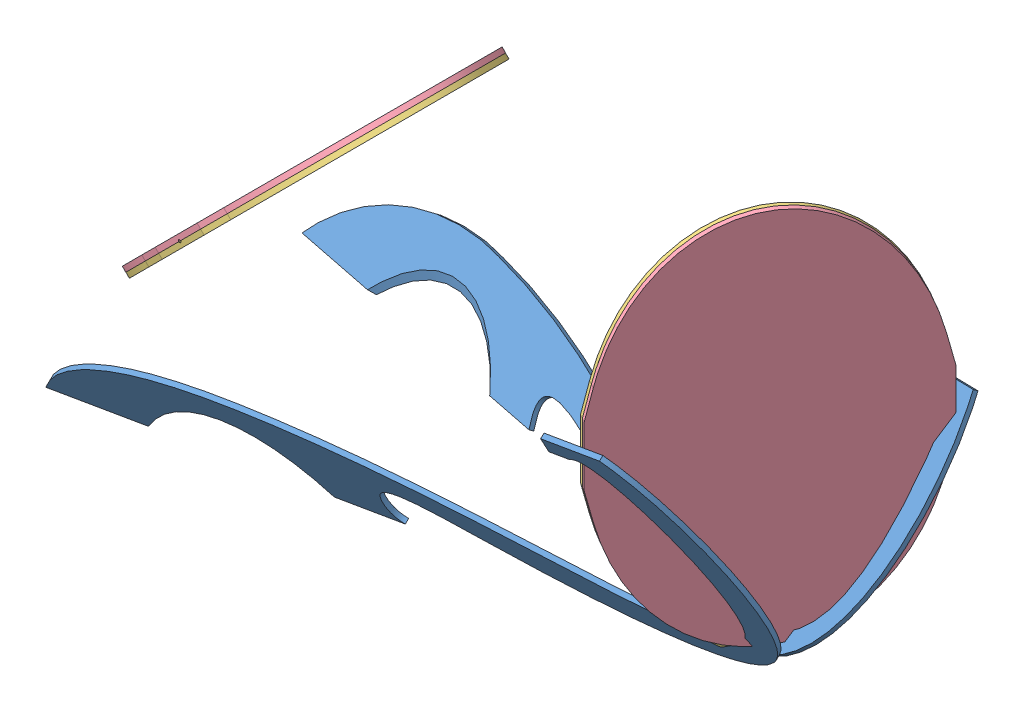
SolidWorks assembly Assem1, configuration Default. Lengths in mm.
Overall size (1381.46 832.52 597.36).
9 component instances, 4 part files, 6 mates.
Components (placement in the parent):
- Angled Side-1: Angled Side [Default] at (-297.1318 -28.8206 176.3727) size (1381.46 807.52 597.36)
- Mirror Assembly-1: Mirror Assembly [Default] at (-287.0354 425.802 60.3644) x (0 0 -1) z (-0.707107 -0.707107 0) size (550 20 760)
  - Mirror-1: Mirror [Default] at (-116.0082 27.9493 42.2276) size (520 4 730)
  - Mirror Front-1: Mirror Front [Default] at (-116.0082 27.9493 42.2276) size (550 10 756.61)
  - Mirror Back-1: Mirror Back [Default] at (-116.0082 27.9493 42.2276) x (-1 0 0) z (0 0 1) size (550 10 760)
- Mirror Assembly-2: Mirror Assembly [Default] at (583.6985 418.407 290.8134) x (-0.5 0 0.866025) z (0 -1 0) size (550 20 760)
  - Mirror-1: Mirror [Default] at (-116.0082 27.9493 42.2276) size (520 4 730)
  - Mirror Front-1: Mirror Front [Default] at (-116.0082 27.9493 42.2276) size (550 10 756.61)
  - Mirror Back-1: Mirror Back [Default] at (-116.0082 27.9493 42.2276) x (-1 0 0) z (0 0 1) size (550 10 760)
Mates (geometry in assembly coordinates):
- Coincident1: coincident: plane of Angled Side-1 through (-499.6318 173.6794 176.3727) normal (0.707107 -0.707107 0); plane of Mirror Assembly-1/Mirror-1
- Coincident2: coincident: point of Angled Side-1; point of Mirror Assembly-1/Mirror Front-1
- Coincident3: coincident: point of Angled Side-1; line of Mirror Assembly-1/Mirror Front-1 through (-297.1318 376.1794 654.5862) axis (0 0 -1)
- Coincident4: coincident: plane of Angled Side-1 through (388.8404 -28.8206 572.4189) normal (-0.866025 0 -0.5); plane of Mirror Assembly-2/Mirror Front-1
- Coincident5: coincident: line of Angled Side-1 through (617.4978 -28.8206 176.3727) axis (0 1 0); line of Mirror Assembly-2/Mirror Front-1 through (617.4978 896.4488 176.3727) axis (0 -1 0)
- Coincident6: coincident: point of Angled Side-1; line of Mirror Assembly-2/Mirror Front-1 through (856.6046 376.1794 -237.7724) axis (-0.5 0 0.866025)
